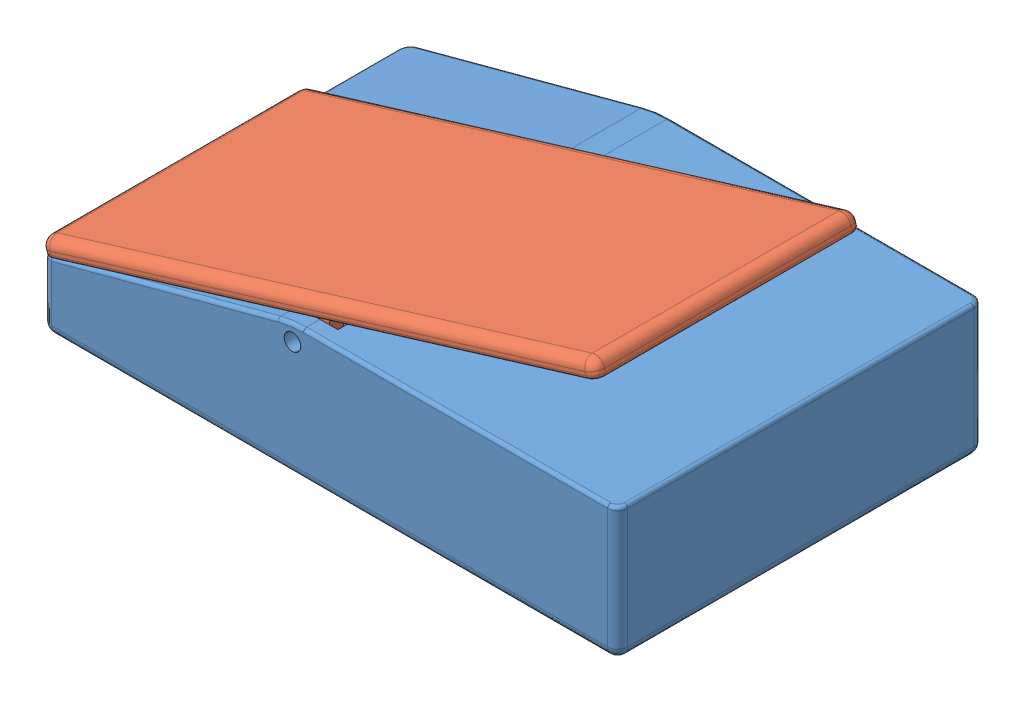
SolidWorks assembly effectPedal, configuration Default. Lengths in mm.
Overall size (174.18 74.98 110).
2 component instances, 2 part files, 2 mates.
Components (placement in the parent):
- effectPedal_Bottom-1: effectPedal_Bottom [Default] at (-43.9145 12.4245 -0.0161) size (172.95 40 110)
- effectPedal_Top-1: effectPedal_Top [Default] at (-110.9629 33.9004 29.9839) x (0.956474 0.291818 0) z (0 0 1) size (174 16.5 80)
Mates (geometry in assembly coordinates):
- Coincident4: coincident: plane of assembly; plane of assembly; plane of effectPedal_Bottom-1 through (-43.9145 12.4245 109.9839) normal (0 0 1); plane of effectPedal_Top-1 through (-110.9629 33.9004 109.9839) normal (0 0 1)
- Concentric1: concentric: cylinder of assembly; cylinder of assembly; cylinder of effectPedal_Bottom-1 through (-108.9202 27.205 109.9859) axis (0 0 -1) radius 2.5; cylinder of effectPedal_Top-1 through (-108.9202 27.205 104.6839) axis (0 0 -1) radius 2.5
